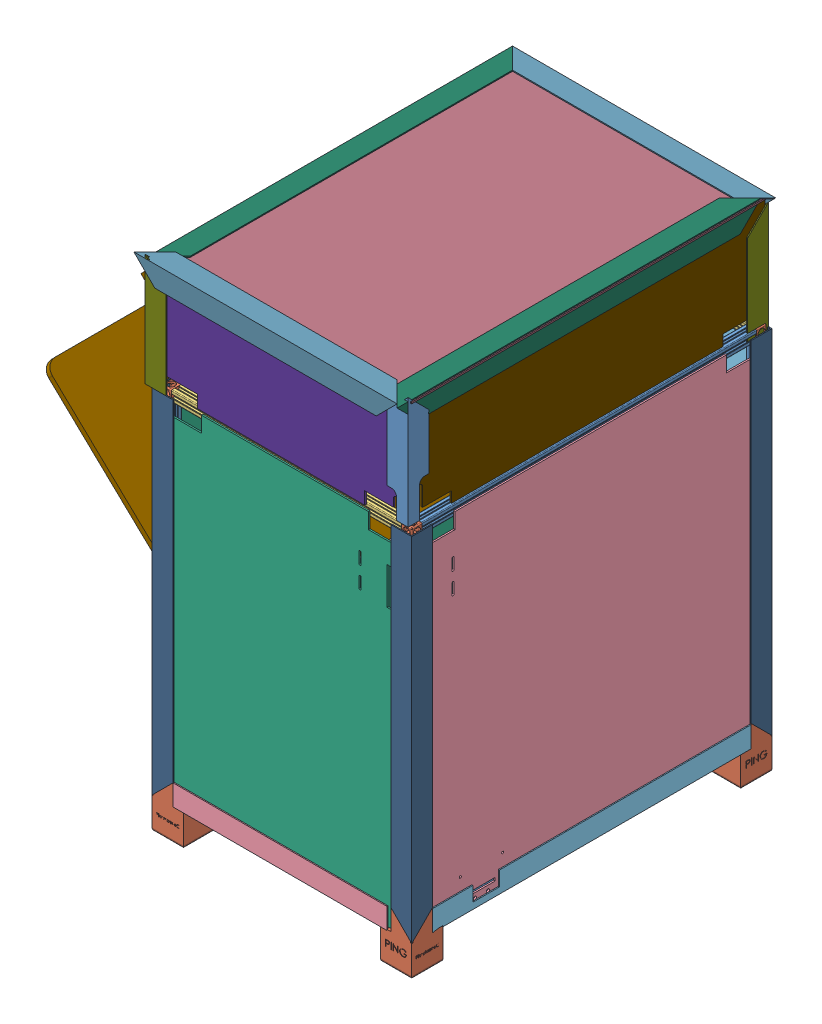
SolidWorks assembly carcasse, configuration Défaut. Lengths in mm.
Overall size (850.58 964 711).
62 component instances, 25 part files, 79 mates.
Components (placement in the parent):
- cadre-1: cadre [Défaut] at (-215.194 -19.8636 -400) size (480 20 680)
  - prof_20x20x600mm-1: prof_20x20x600mm [End Finishing_Non-Machined End Finish Options_Type_Single_] at (-14.8937 4.0689 600) size (20 20 640)
  - Blocks-1: Blocks [Défaut] at (-4.8937 14.0689 1240) x (0 1 0) z (0 0 1) size (20 20 20)
  - prof_20x20x600mm-3: prof_20x20x600mm [End Finishing_Non-Machined End Finish Options_Type_Single_] at (445.1063 4.0689 600) size (20 20 640)
  - Blocks-3: Blocks [Défaut] at (-4.8937 -5.9311 580) x (0 0 -1) z (0 1 0) size (20 20 20)
  - Blocks-4: Blocks [Défaut] at (435.1063 14.0689 600) x (0 1 0) z (0 0 -1) size (20 20 20)
  - Blocks-5: Blocks [Défaut] at (435.1063 -5.9311 1260) x (0 0 1) z (0 1 0) size (20 20 20)
  - prof_20x20x400mm-1: prof_20x20x400mm [End Finishing_Non-Machined End Finish Options_Type_Single_] at (435.1063 4.0689 590) x (0 0 1) z (-1 0 0) size (20 20 440)
  - prof_20x20x400mm-2: prof_20x20x400mm [End Finishing_Non-Machined End Finish Options_Type_Single_] at (435.1063 4.0689 1250) x (0 0 1) z (-1 0 0) size (20 20 440)
- prof_20x20x600mm-1: prof_20x20x600mm [End Finishing_Non-Machined End Finish Options_Type_Single_] at (229.9123 -25.7947 190) x (1 0 0) z (0 -1 0) size (20 20 640)
- prof_20x20x600mm-2: prof_20x20x600mm [End Finishing_Non-Machined End Finish Options_Type_Single_] at (229.9123 -25.7947 850) x (1 0 0) z (0 -1 0) size (20 20 640)
- prof_20x20x600mm-3: prof_20x20x600mm [End Finishing_Non-Machined End Finish Options_Type_Single_] at (-230.0877 -25.7947 850) x (1 0 0) z (0 -1 0) size (20 20 640)
- prof_20x20x600mm-4: prof_20x20x600mm [End Finishing_Non-Machined End Finish Options_Type_Single_] at (-230.0877 -25.7947 190) x (1 0 0) z (0 -1 0) size (20 20 640)
- cadre-2: cadre [Défaut] at (215.0186 -671.7258 -400) x (-1 0 0) z (0 0 1) size (480 20 680)
  - prof_20x20x600mm-1: prof_20x20x600mm [End Finishing_Non-Machined End Finish Options_Type_Single_] at (-14.8937 4.0689 600) size (20 20 640)
  - Blocks-1: Blocks [Défaut] at (-4.8937 14.0689 1240) x (0 1 0) z (0 0 1) size (20 20 20)
  - prof_20x20x600mm-3: prof_20x20x600mm [End Finishing_Non-Machined End Finish Options_Type_Single_] at (445.1063 4.0689 600) size (20 20 640)
  - Blocks-3: Blocks [Défaut] at (-4.8937 -5.9311 580) x (0 0 -1) z (0 1 0) size (20 20 20)
  - Blocks-4: Blocks [Défaut] at (435.1063 14.0689 600) x (0 1 0) z (0 0 -1) size (20 20 20)
  - Blocks-5: Blocks [Défaut] at (435.1063 -5.9311 1260) x (0 0 1) z (0 1 0) size (20 20 20)
  - prof_20x20x400mm-1: prof_20x20x400mm [End Finishing_Non-Machined End Finish Options_Type_Single_] at (435.1063 4.0689 590) x (0 0 1) z (-1 0 0) size (20 20 440)
  - prof_20x20x400mm-2: prof_20x20x400mm [End Finishing_Non-Machined End Finish Options_Type_Single_] at (435.1063 4.0689 1250) x (0 0 1) z (-1 0 0) size (20 20 440)
- plaque_acrylique_680x670-2: plaque_acrylique_680x670 [Défaut] at (239.9123 -350.7947 520) x (0 0 -1) z (1 0 0) size (680 670 3)
- plaque_acrylique_380x670_G-1: plaque_acrylique_380x670_G [Défaut] at (49.9123 -350.7947 177) size (480 670 3)
- plaque_acrylique_680x670_porte-1: plaque_acrylique_680x670_porte [Défaut] at (-250.0877 -350.7947 520) x (0 0 -1) z (1 0 0) size (680 670 10)
- charniere-1: charniere [Défaut] at (-243.7309 -495.7947 776.2875) x (0 0 1) z (0 -1 0) size (40 29.08 53.23)
  - axe charnière-1: axe charnière [Défaut] at (-76.2875 9.8568 0) size (40 5 5)
  - batant charnière-1: batant charnière [Défaut] at (-76.2875 10.1991 -17.6196) size (40 7 33.5)
  - batant charnière-2: batant charnière [Défaut] at (-36.2875 -2.6626 12.4029) x (-1 0 0) z (0 0.723942 -0.689861) size (40 7 33.5)
- charniere-2: charniere [Défaut] at (-243.7309 -495.7947 376.2875) x (0 0 1) z (0 -1 0) size (40 29.08 53.23)
  - axe charnière-1: axe charnière [Défaut] at (-76.2875 9.8568 0) size (40 5 5)
  - batant charnière-1: batant charnière [Défaut] at (-76.2875 10.1991 -17.6196) size (40 7 33.5)
  - batant charnière-2: batant charnière [Défaut] at (-36.2875 -2.6626 12.4029) x (-1 0 0) z (0 0.723942 -0.689861) size (40 7 33.5)
- porte-1: porte [Défaut] at (-356.1448 -393.231 520) x (0 0 -1) z (0.689861 0.723942 0) size (480 480 10)
- eclisse_40x40x670_bisote_x1-1: eclisse_40x40x670_bisote_x1 [Défaut] at (-232.0877 -690.7947 195.1136) size (40 675 40)
- eclisse_40x40x670_bisote_x1-2: eclisse_40x40x670_bisote_x1 [Défaut] at (-231.9741 -690.7947 845) x (0 0 -1) z (1 0 0) size (40 675 40)
- eclisse_40x40x670_bisote_x1-3: eclisse_40x40x670_bisote_x1 [Défaut] at (224.9123 -688.7947 844.8864) x (-1 0 0) z (0 0 -1) size (40 675 40)
- eclisse_40x40x670_bisote_x1-4: eclisse_40x40x670_bisote_x1 [Défaut] at (224.7986 -688.7947 195) x (0 0 1) z (-1 0 0) size (40 675 40)
- couvercle-1: couvercle [Défaut] at (237.4119 97.9268 872) size (525 236 711)
  - plaque_acrylique_680x210-2: plaque_acrylique_680x210 [Défaut] at (-487.4996 -1.7215 -352) x (0 0 -1) z (1 0 0) size (680 210 3)
  - plaque_acrylique_380x210-2: plaque_acrylique_380x210 [Défaut] at (-194.4996 -8.7215 -695) size (480 210 3)
  - plaque_acrylique_380x680-1: plaque_acrylique_380x680 [Défaut] at (-187.4996 103.2785 -352) x (1 0 0) z (0 1 0) size (480 680 3)
  - eclisse_40x40x404_bisote_x2-1: eclisse_40x40x404_bisote_x2 [Défaut] at (14.5004 88.1649 -677) x (0 0 1) z (0 -1 0) size (40 504 40)
  - eclisse_40x40x704_bisote_x2-1: eclisse_40x40x704_bisote_x2 [Défaut] at (-19.6132 88.2785 -683) x (0 -1 0) z (-1 0 0) size (40 697 40)
  - eclisse_40x40x404_bisote_x2-2: eclisse_40x40x404_bisote_x2 [Défaut] at (-510.4996 88.1649 -13) x (0 0 -1) z (0 -1 0) size (40 504 40)
  - eclisse_40x40x704_bisote_x2-2: eclisse_40x40x704_bisote_x2 [Défaut] at (-469.4996 88.1649 -697) x (1 0 0) z (0 -1 0) size (40 697 40)
  - eclisse_40x40x222_bisote_x1-1: eclisse_40x40x222_bisote_x1 [Défaut] at (-469.386 108.2785 -677) x (0 0 1) z (1 0 0) size (40 215 40)
  - eclisse_40x40x222_bisote_x1-2: eclisse_40x40x222_bisote_x1 [Défaut] at (-19.4996 94.2785 -676.8864) x (-1 0 0) z (0 0 1) size (40 215 40)
  - eclisse_40x40x222_bisote_x1-4: eclisse_40x40x222_bisote_x1 [Défaut] at (-469.4996 115.2785 -13.1136) x (1 0 0) z (0 0 -1) size (40 215 40)
  - plaque_acrylique_380x210_Moteur-1: plaque_acrylique_380x210_Moteur [Défaut] at (-194.4996 -1.7215 -12) size (480 210 3)
  - plaque_acrylique_680x210_moteur-1: plaque_acrylique_680x210_moteur [Défaut] at (-4.4996 -1.7215 -352) x (0 0 -1) z (1 0 0) size (680 210 3)
  - eclisse_40x40x222_bisote_x1_Moteur-1: eclisse_40x40x222_bisote_x1_Moteur [Défaut] at (-19.6132 115.2785 -27) x (0 0 -1) z (-1 0 0) size (40 215 40)
- Pied-1: Pied [Défaut] at (184.9123 -688.7947 235) x (-1 0 0) z (0 -1 0) size (60 60 100)
- Pied-2: Pied [Défaut] at (184.9123 -688.7947 805) x (0 0 -1) z (0 -1 0) size (60 60 100)
- Pied-3: Pied [Défaut] at (-192.0877 -690.7947 805) x (1 0 0) z (0 -1 0) size (60 60 100)
- Pied-4: Pied [Défaut] at (-192.0877 -688.7947 235) x (0 0 1) z (0 -1 0) size (60 60 100)
- eclisse_bas_40x40x704-2: eclisse_bas_40x40x704 [Défaut] at (-232.0877 -670.681 825) x (1 0 0) z (0 1 0) size (40 610 40)
- eclisse_bas_40x40x404-1: eclisse_bas_40x40x404 [Défaut] at (-205.0877 -670.681 195) x (0 0 1) z (0 1 0) size (40 410 40)
- eclisse_bas_40x40x404-2: eclisse_bas_40x40x404 [Défaut] at (197.9123 -670.681 845) x (0 0 -1) z (0 1 0) size (40 410 40)
- eclisse_bas_support_Z_40x40x704-1: eclisse_bas_support_Z_40x40x704 [Défaut] at (224.7986 -670.7947 825) x (0 1 0) z (-1 0 0) size (40 610 40)
- plaque_acrylique_380x670_D-2: plaque_acrylique_380x670_D [Défaut] at (-50.0877 -350.7947 863) x (-1 0 0) z (0 0 -1) size (480 670 3)
- plaque_acrylique_bas_380x680-1: plaque_acrylique_bas_380x680 [Défaut] at (49.9123 -688.7947 520) x (1 0 0) z (0 1 0) size (480 680 3)
Mates (geometry in assembly coordinates):
- Coïncidente50: coincident anti-aligned: plane of plaque_acrylique_680x670_porte-1 through (-250.0877 -350.7947 520) normal (-1 0 0); plane of charniere-1/batant charnière-1 through (-250.0877 -535.7947 740) normal (1 0 0)
- Coïncidente51: coincident anti-aligned: plane of plaque_acrylique_680x670_porte-1 through (-250.0877 -350.7947 520) normal (-1 0 0); plane of charniere-2/batant charnière-1 through (-250.0877 -535.7947 340) normal (1 0 0)
- Distance4: distance = 20 mm anti-aligned: plane of charniere-2/batant charnière-1 through (-253.5877 -495.7947 300) normal (0 0 -1); plane of plaque_acrylique_680x670_porte-1 through (-250.0877 -75.7947 280) normal (0 0 1)
- Coïncidente54: coincident aligned: line of plaque_acrylique_680x670_porte-1 through (-250.0877 -495.7947 740) axis (0 0 -1); line of charniere-2/batant charnière-1 through (-250.0877 -495.7947 340) axis (0 0 -1)
- Distance5: distance = 20 mm anti-aligned: plane of plaque_acrylique_680x670_porte-1 through (-250.0877 -75.7947 760) normal (0 0 -1); plane of charniere-1/batant charnière-1 through (-253.5877 -495.7947 740) normal (0 0 1)
- Coïncidente57: coincident aligned: line of plaque_acrylique_680x670_porte-1 through (-250.0877 -495.7947 740) axis (0 0 -1); line of charniere-1/batant charnière-1 through (-250.0877 -495.7947 740) axis (0 0 -1)
- Coïncidente62: coincident anti-aligned: plane of charniere-1/batant charnière-2 through (-280.1309 -465.6664 700) normal (0.689861 0.723942 0); plane of porte-1 through (-576.947 -182.8234 550) normal (-0.689861 -0.723942 0)
- Coïncidente63: coincident anti-aligned: line of charniere-1/batant charnière-2 through (-251.1732 -493.2609 720) axis (0 0 1); line of porte-1 through (-251.1732 -493.2609 740) axis (0 0 -1)
- Coïncidente64: coincident anti-aligned: plane of plaque_acrylique_680x670_porte-1 through (-250.0877 -75.7947 760) normal (0 0 -1); plane of porte-1 through (-548.3301 -196.2798 760) normal (0 0 1)
- Coïncidente66: coincident anti-aligned: plane of plaque_acrylique_680x670_porte-1 through (-250.0877 -350.7947 520) normal (-1 0 0); plane of eclisse_40x40x670_bisote_x1-1 through (-250.0877 -15.7947 177) normal (1 0 0)
- Coïncidente67: coincident aligned: plane of plaque_acrylique_680x670_porte-1 through (-240.0877 -15.7947 860) normal (0 1 0); plane of eclisse_40x40x670_bisote_x1-1 through (-232.0877 -15.7947 195.1136) normal (0 1 0)
- Coïncidente68: coincident anti-aligned: plane of plaque_acrylique_680x670-2 through (242.9123 -350.7947 520) normal (1 0 0); plane of eclisse_40x40x670_bisote_x1-4 through (242.9123 -13.7947 177) normal (-1 0 0)
- Coïncidente72: coincident anti-aligned: plane of plaque_acrylique_680x670_porte-1 through (-250.0877 -350.7947 520) normal (-1 0 0); plane of eclisse_40x40x670_bisote_x1-2 through (-250.0877 -15.7947 863) normal (1 0 0)
- Coïncidente74: coincident anti-aligned: plane of plaque_acrylique_680x670-2 through (242.9123 -350.7947 520) normal (1 0 0); plane of eclisse_40x40x670_bisote_x1-3 through (242.9123 -13.7947 863) normal (-1 0 0)
- Coïncidente100: coincident: plane of plaque_acrylique_680x670_porte-1 through (-240.0877 -15.7947 860) normal (0 1 0); line of eclisse_40x40x670_bisote_x1-2 through (-250.0877 -15.7947 863) axis (0 0 -1)
- Coïncidente126: coincident anti-aligned: plane of eclisse_40x40x670_bisote_x1-3 through (244.9123 -688.7947 275) normal (-0.707107 -0.707107 0); plane of Pied-2 through (204.9123 -648.7947 863) normal (0.707107 0.707107 0)
- Coïncidente130: coincident anti-aligned: plane of eclisse_40x40x670_bisote_x1-2 through (337.9123 -690.7947 865) normal (0 -0.707107 -0.707107); plane of Pied-3 through (-250.0877 -650.7947 825) normal (0 0.707107 0.707107)
- Coïncidente132: coincident anti-aligned: plane of plaque_acrylique_680x670_porte-1 through (-250.0877 -350.7947 520) normal (-1 0 0); plane of eclisse_bas_40x40x704-2 through (-250.0877 -688.7947 215) normal (1 0 0)
- Coïncidente134: coincident anti-aligned: line of eclisse_40x40x670_bisote_x1-2 through (-252.0877 -15.7947 825) axis (0 -1 0); line of eclisse_bas_40x40x704-2 through (-252.0877 -690.7947 825) axis (0 1 0)
- Coïncidente140: coincident anti-aligned: line of Pied-3 through (-212.0877 -650.7947 865) axis (0 -1 0); line of eclisse_bas_40x40x404-2 through (-212.0877 -690.7947 865) axis (0 1 0)
- Coïncidente142: coincident anti-aligned: plane of plaque_acrylique_680x670-2 through (242.9123 -350.7947 520) normal (1 0 0); plane of eclisse_bas_support_Z_40x40x704-1 through (242.9123 -688.7947 215) normal (-1 0 0)
- Coïncidente144: coincident anti-aligned: plane of Pied-2 through (242.9123 -648.7947 825) normal (0 0 -1); plane of eclisse_bas_support_Z_40x40x704-1 through (224.7986 -670.7947 825) normal (0 0 1)
- Coïncidente151: coincident anti-aligned: plane of Pied-3 through (-192.0877 -690.7947 805) normal (0 1 0); plane of eclisse_bas_40x40x404-2 through (-212.0877 -690.7947 865) normal (0 -1 0)
- Coïncidente156: coincident anti-aligned: plane of eclisse_bas_40x40x404-2 through (-212.0877 -688.7947 863) normal (0 0 -1); plane of plaque_acrylique_380x670_D-2 through (-50.0877 -350.7947 863) normal (0 0 1)
- Coïncidente157: coincident anti-aligned: plane of eclisse_40x40x670_bisote_x1-2 through (-250.0877 -15.7947 863) normal (0 0 -1); plane of plaque_acrylique_380x670_D-2 through (-50.0877 -350.7947 863) normal (0 0 1)
- Coïncidente158: coincident anti-aligned: plane of eclisse_40x40x670_bisote_x1-3 through (242.9123 -13.7947 863) normal (0 0 -1); plane of plaque_acrylique_380x670_D-2 through (-50.0877 -350.7947 863) normal (0 0 1)
- Coïncidente163: coincident anti-aligned: plane of cadre-1/Blocks-1 through (-240.0877 -25.7947 860) normal (0 -1 0); plane of prof_20x20x600mm-3 through (-238.5877 -25.7947 858.5) normal (0 1 0)
- Coïncidente164: coincident aligned: plane of cadre-1/Blocks-1 through (-240.0877 -25.7947 860) normal (-1 0 0); plane of prof_20x20x600mm-3 through (-240.0877 -665.7947 853.75) normal (-1 0 0)
- Coïncidente165: coincident aligned: plane of cadre-1/Blocks-1 through (-220.0877 -5.7947 860) normal (0 0 1); plane of prof_20x20x600mm-3 through (-233.8377 -665.7947 860) normal (0 0 1)
- Coïncidente166: coincident anti-aligned: plane of prof_20x20x600mm-3 through (-238.5877 -665.7947 858.5) normal (0 -1 0); plane of cadre-2/Blocks-5 through (-220.0877 -665.7947 860) normal (0 1 0)
- Coïncidente167: coincident aligned: plane of prof_20x20x600mm-3 through (-233.8377 -665.7947 860) normal (0 0 1); plane of cadre-2/Blocks-5 through (-240.0877 -685.7947 860) normal (0 0 1)
- Coïncidente168: coincident aligned: plane of prof_20x20x600mm-3 through (-240.0877 -665.7947 853.75) normal (-1 0 0); plane of cadre-2/Blocks-5 through (-240.0877 -685.7947 840) normal (-1 0 0)
- Coïncidente169: coincident anti-aligned: plane of prof_20x20x600mm-2 through (221.4123 -665.7947 858.5) normal (0 -1 0); plane of cadre-2/Blocks-1 through (239.9123 -665.7947 860) normal (0 1 0)
- Coïncidente170: coincident aligned: plane of prof_20x20x600mm-2 through (226.1623 -665.7947 860) normal (0 0 1); plane of cadre-2/Blocks-1 through (219.9123 -685.7947 860) normal (0 0 1)
- Coïncidente171: coincident aligned: plane of prof_20x20x600mm-2 through (239.9123 -665.7947 853.75) normal (1 0 0); plane of cadre-2/Blocks-1 through (239.9123 -665.7947 860) normal (1 0 0)
- Coïncidente172: coincident anti-aligned: plane of prof_20x20x600mm-1 through (221.4123 -665.7947 198.5) normal (0 -1 0); plane of cadre-2/Blocks-3 through (219.9123 -665.7947 180) normal (0 1 0)
- Coïncidente173: coincident aligned: plane of prof_20x20x600mm-1 through (239.9123 -665.7947 193.75) normal (1 0 0); plane of cadre-2/Blocks-3 through (239.9123 -685.7947 200) normal (1 0 0)
- Coïncidente174: coincident aligned: plane of prof_20x20x600mm-1 through (233.6623 -665.7947 180) normal (0 0 -1); plane of cadre-2/Blocks-3 through (239.9123 -685.7947 180) normal (0 0 -1)
- Coïncidente175: coincident aligned: plane of cadre-1/Blocks-3 through (-240.0877 -5.7947 200) normal (-1 0 0); plane of prof_20x20x600mm-4 through (-240.0877 -665.7947 186.25) normal (-1 0 0)
- Coïncidente176: coincident aligned: plane of cadre-1/Blocks-3 through (-240.0877 -5.7947 180) normal (0 0 -1); plane of prof_20x20x600mm-4 through (-233.8377 -665.7947 180) normal (0 0 -1)
- Coïncidente177: coincident anti-aligned: plane of cadre-1/Blocks-3 through (-220.0877 -25.7947 180) normal (0 -1 0); plane of prof_20x20x600mm-4 through (-238.5877 -25.7947 198.5) normal (0 1 0)
- Coïncidente183: coincident aligned: plane of prof_20x20x600mm-2 through (239.9123 -665.7947 853.75) normal (1 0 0); plane of plaque_acrylique_380x670_D-2 through (239.9123 -15.7947 860) normal (1 0 0)
- Coïncidente185: coincident anti-aligned: plane of cadre-1/prof_20x20x600mm-3 through (239.9123 -12.0447 840) normal (1 0 0); plane of plaque_acrylique_680x670-2 through (239.9123 -350.7947 520) normal (-1 0 0)
- Coïncidente186: coincident aligned: plane of cadre-1/prof_20x20x400mm-2 through (-220.0877 -12.0447 860) normal (0 0 1); plane of plaque_acrylique_680x670-2 through (242.9123 -15.7947 860) normal (0 0 1)
- Coïncidente187: coincident aligned: plane of cadre-1/prof_20x20x400mm-1 through (-220.0877 -19.5447 180) normal (0 0 -1); plane of plaque_acrylique_680x670_porte-1 through (-240.0877 -15.7947 180) normal (0 0 -1)
- Coïncidente191: coincident anti-aligned: plane of cadre-2/prof_20x20x400mm-1 through (219.9123 -685.7947 193.75) normal (0 -1 0); plane of plaque_acrylique_bas_380x680-1 through (49.9123 -685.7947 520) normal (0 1 0)
- Coïncidente192: coincident aligned: plane of cadre-2/prof_20x20x400mm-2 through (219.9123 -679.5447 860) normal (0 0 1); plane of plaque_acrylique_bas_380x680-1 through (-240.0877 -685.7947 860) normal (0 0 1)
- Coïncidente193: coincident aligned: plane of cadre-2/prof_20x20x600mm-1 through (239.9123 -679.5447 840) normal (1 0 0); plane of plaque_acrylique_bas_380x680-1 through (239.9123 -685.7947 180) normal (1 0 0)
- Coïncidente195: coincident anti-aligned: plane of Pied-2 through (184.9123 -688.7947 805) normal (0 1 0); plane of plaque_acrylique_bas_380x680-1 through (49.9123 -688.7947 520) normal (0 -1 0)
- Coïncidente198: coincident anti-aligned: plane of Pied-1 through (184.9123 -688.7947 235) normal (0 1 0); plane of plaque_acrylique_bas_380x680-1 through (49.9123 -688.7947 520) normal (0 -1 0)
- Coïncidente199: coincident anti-aligned: line of eclisse_40x40x670_bisote_x1-4 through (244.9123 -688.7947 175) axis (0 0.707107 0.707107); line of Pied-1 through (244.9123 -648.7947 215) axis (0 -0.707107 -0.707107)
- Coïncidente200: coincident anti-aligned: plane of Pied-2 through (184.9123 -688.7947 805) normal (0 1 0); plane of plaque_acrylique_bas_380x680-1 through (49.9123 -688.7947 520) normal (0 -1 0)
- Coïncidente201: coincident anti-aligned: plane of plaque_acrylique_680x670-2 through (242.9123 -350.7947 520) normal (1 0 0); plane of Pied-2 through (242.9123 -648.7947 863) normal (-1 0 0)
- Coïncidente202: coincident anti-aligned: line of eclisse_40x40x670_bisote_x1-3 through (244.9123 -688.7947 865) axis (-0.707107 0.707107 0); line of Pied-2 through (204.9123 -648.7947 865) axis (0.707107 -0.707107 0)
- Coïncidente203: coincident aligned: plane of cadre-2/prof_20x20x600mm-3 through (-233.8377 -685.7947 840) normal (0 -1 0); plane of plaque_acrylique_680x670_porte-1 through (-240.0877 -685.7947 860) normal (0 -1 0)
- Coïncidente204: coincident anti-aligned: plane of prof_20x20x600mm-1 through (233.6623 -665.7947 180) normal (0 0 -1); plane of plaque_acrylique_380x670_G-1 through (49.9123 -350.7947 180) normal (0 0 1)
- Coïncidente205: coincident aligned: plane of cadre-2/prof_20x20x400mm-1 through (219.9123 -685.7947 186.25) normal (0 -1 0); plane of plaque_acrylique_380x670_G-1 through (-240.0877 -685.7947 180) normal (0 -1 0)
- Coïncidente206: coincident aligned: plane of prof_20x20x600mm-1 through (239.9123 -665.7947 186.25) normal (1 0 0); plane of plaque_acrylique_380x670_G-1 through (239.9123 -15.7947 180) normal (1 0 0)
- Coïncidente207: coincident anti-aligned: plane of prof_20x20x600mm-4 through (-240.0877 -665.7947 186.25) normal (-1 0 0); plane of plaque_acrylique_680x670_porte-1 through (-240.0877 -350.7947 520) normal (1 0 0)
- Coïncidente208: coincident anti-aligned: plane of plaque_acrylique_380x670_G-1 through (49.9123 -350.7947 177) normal (0 0 -1); plane of eclisse_40x40x670_bisote_x1-1 through (-250.0877 -15.7947 177) normal (0 0 1)
- Coïncidente210: coincident anti-aligned: plane of plaque_acrylique_380x670_G-1 through (49.9123 -350.7947 177) normal (0 0 -1); plane of eclisse_40x40x670_bisote_x1-4 through (242.9123 -13.7947 177) normal (0 0 1)
- Coïncidente211: coincident anti-aligned: plane of Pied-4 through (-192.0877 -688.7947 235) normal (0 1 0); plane of plaque_acrylique_bas_380x680-1 through (49.9123 -688.7947 520) normal (0 -1 0)
- Parallèle4: parallel anti-aligned: line of eclisse_40x40x670_bisote_x1-1 through (-252.0877 -690.7947 175) axis (0.707107 0.707107 0); line of Pied-4 through (-212.0877 -648.7947 175) axis (-0.707107 -0.707107 0)
- Coïncidente215: coincident aligned: plane of plaque_acrylique_680x670_porte-1 through (-250.0877 -350.7947 520) normal (-1 0 0); plane of couvercle-1/plaque_acrylique_680x210-2 through (-250.0877 96.2053 520) normal (-1 0 0)
- Coïncidente216: coincident aligned: plane of couvercle-1/plaque_acrylique_380x210_Moteur-1 through (42.9123 96.2053 863) normal (0 0 1); plane of plaque_acrylique_380x670_D-2 through (-50.0877 -350.7947 863) normal (0 0 1)
- Coïncidente217: coincident aligned: plane of cadre-2/prof_20x20x600mm-1 through (233.6623 -685.7947 840) normal (0 -1 0); plane of plaque_acrylique_680x670-2 through (242.9123 -685.7947 860) normal (0 -1 0)
- Coïncidente218: coincident: plane of cadre-2/prof_20x20x400mm-2 through (219.9123 -685.7947 853.75) normal (0 -1 0); line of plaque_acrylique_380x670_D-2 through (239.9123 -685.7947 863) axis (-1 0 0)
- Coïncidente219: coincident aligned: plane of couvercle-1/plaque_acrylique_380x210_Moteur-1 through (42.9123 96.2053 863) normal (0 0 1); plane of plaque_acrylique_380x670_D-2 through (-50.0877 -350.7947 863) normal (0 0 1)
- Coïncidente221: coincident aligned: plane of plaque_acrylique_680x670_porte-1 through (-250.0877 -350.7947 520) normal (-1 0 0); plane of couvercle-1/plaque_acrylique_680x210-2 through (-250.0877 96.2053 520) normal (-1 0 0)
- Coïncidente222: coincident anti-aligned: line of plaque_acrylique_380x670_G-1 through (159.9123 -15.7947 177) axis (-1 0 0); line of couvercle-1/plaque_acrylique_380x210-2 through (-167.0877 -15.7947 177) axis (1 0 0)
- Coïncidente223: coincident anti-aligned: plane of eclisse_bas_support_Z_40x40x704-1 through (242.9123 -688.7947 215) normal (0 1 0); plane of plaque_acrylique_bas_380x680-1 through (49.9123 -688.7947 520) normal (0 -1 0)
- Coïncidente224: coincident anti-aligned: plane of eclisse_bas_40x40x704-2 through (-250.0877 -688.7947 215) normal (0 1 0); plane of plaque_acrylique_bas_380x680-1 through (49.9123 -688.7947 520) normal (0 -1 0)
- Coïncidente225: coincident anti-aligned: plane of plaque_acrylique_380x670_G-1 through (49.9123 -350.7947 177) normal (0 0 -1); plane of eclisse_bas_40x40x404-1 through (204.9123 -688.7947 177) normal (0 0 1)
- Coïncidente226: coincident anti-aligned: plane of eclisse_bas_40x40x404-1 through (204.9123 -688.7947 177) normal (0 1 0); plane of plaque_acrylique_bas_380x680-1 through (49.9123 -688.7947 520) normal (0 -1 0)
- Coïncidente227: coincident anti-aligned: plane of Pied-1 through (204.9123 -648.7947 177) normal (-1 0 0); plane of eclisse_bas_40x40x404-1 through (204.9123 -670.681 195) normal (1 0 0)
- Coïncidente228: coincident anti-aligned: plane of plaque_acrylique_680x670_porte-1 through (-250.0877 -350.7947 520) normal (-1 0 0); plane of Pied-3 through (-250.0877 -650.7947 825) normal (1 0 0)
- Coïncidente229: coincident anti-aligned: plane of plaque_acrylique_380x670_G-1 through (49.9123 -350.7947 177) normal (0 0 -1); plane of Pied-4 through (-212.0877 -648.7947 177) normal (0 0 1)
- Coïncidente230: coincident anti-aligned: plane of plaque_acrylique_680x670_porte-1 through (-250.0877 -350.7947 520) normal (-1 0 0); plane of Pied-4 through (-250.0877 -648.7947 177) normal (1 0 0)
- Coïncidente231: coincident anti-aligned: plane of plaque_acrylique_380x670_G-1 through (49.9123 -350.7947 177) normal (0 0 -1); plane of Pied-1 through (242.9123 -648.7947 177) normal (0 0 1)
